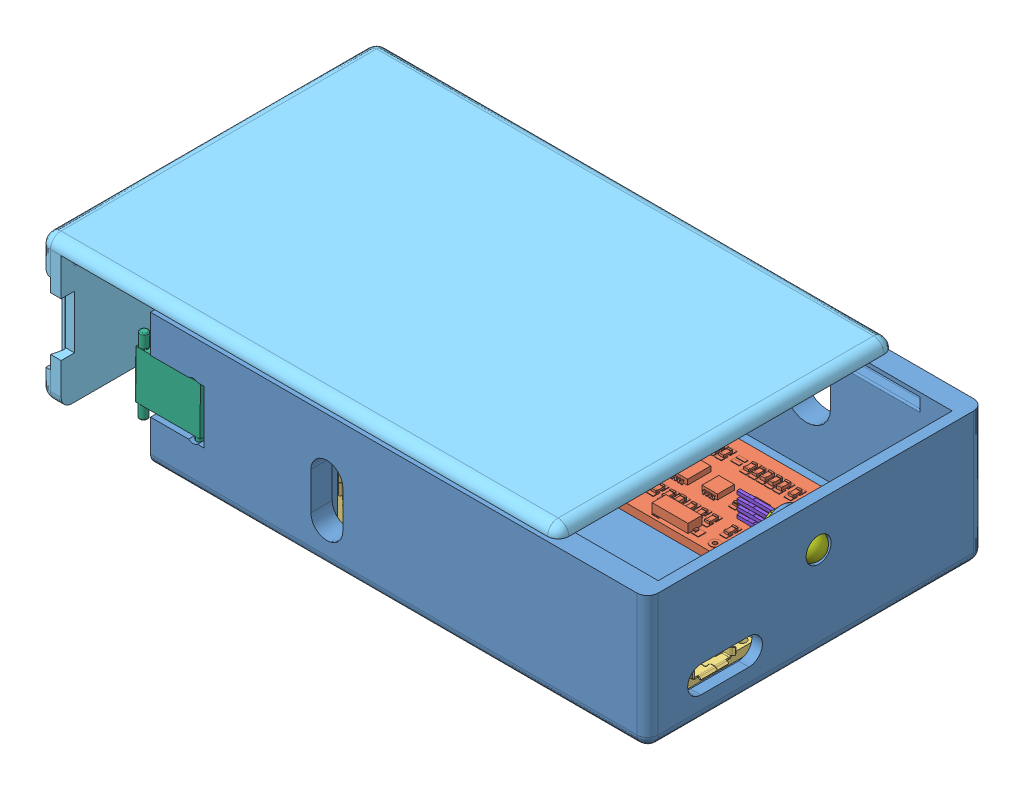
SolidWorks assembly EMG Assembly, configuration Default. Lengths in mm.
Overall size (115.32 27 63.8).
11 component instances, 8 part files, 4 mates.
Components (placement in the parent):
- EMG box-1: EMG box [Default] at (-2.9613 60.7391 32.8742) x (1 0 0) z (0 0 -1) size (93 25 63)
- myoware.step-1: myoware.step [Default] at (36.0075 39.3951 62.4733) size (52.81 5.42 21.62)
- Arduino Nano 33 IoT-1: Arduino Nano 33 IoT [Default] at (66.7291 39.9126 81.2418) x (0 0 -1) z (1 0 0) size (17.78 5.55 45.32)
- 9V-battery-1: 9V-battery [Default] at (32.7872 54.8835 -1.332) x (1 0 0) z (0 -1 0) size (26.04 47.88 17.14)
- EMG Box Lid-1: EMG Box Lid [Default] at (-22.4862 60.7391 95.0742) x (0 1 0) z (0 0 -1) size (27 97 63)
- Box Locking Part-1: Box Locking Part [Default] at (7.7324 53.2338 33.7892) x (-1 0 0) z (0 1 0) size (12.2 1.5 14)
- Box Locking Part-2: Box Locking Part [Default] at (7.6978 44.1967 95.2744) x (-1 0 0) z (0 -0.999962 0.008727) size (12.2 1.5 14)
- Arduino Nano 33 IoT-2: Arduino Nano 33 IoT [Default] at (29.5766 47.2765 68.6704) x (0 -1 0) z (0 0 1) size (17.78 5.55 45.32)
- Led RGB 5mm-1: Led RGB 5mm [Valor predeterminado] at (79.0387 52.7391 63.8742) x (0 -1 0) z (0 0 1) size (5.6 15.8 5.8)
  - Lente^Led RGB 5mm-1: Lente^Led RGB 5mm [Valor predeterminado] at origin size (5.6 8.8 5.8) (virtual)
  - Terminais^Led RGB 5mm-1: Terminais^Led RGB 5mm [Valor predeterminado] at origin size (4.82 11.92 1.55) (virtual)
Mates (geometry in assembly coordinates):
- Coincident1: coincident anti-aligned: plane of EMG box-1 through (-2.9613 60.7391 32.8742) normal (0 1 0); plane of EMG Box Lid-1 through (74.5138 60.7391 32.0742) normal (0 -1 0)
- Coincident2: coincident anti-aligned: plane of EMG box-1 through (84.0387 59.9891 34.6742) normal (0 0 1); plane of EMG Box Lid-1 through (60.5138 59.2391 34.6742) normal (0 0 -1)
- Concentric1: concentric anti-aligned: cone of EMG box-1 through (92.0387 52.7391 63.8742) axis (1 0 0); cylinder of Led RGB 5mm-1/Lente^Led RGB 5mm-1 through (92.8387 52.7391 63.8742) axis (-1 0 0) radius 2.5
- Coincident3: coincident anti-aligned: plane of EMG box-1 through (85.0387 52.7391 63.8742) normal (-1 0 0); plane of Led RGB 5mm-1/Lente^Led RGB 5mm-1 through (85.0387 52.7391 63.8742) normal (1 0 0)
